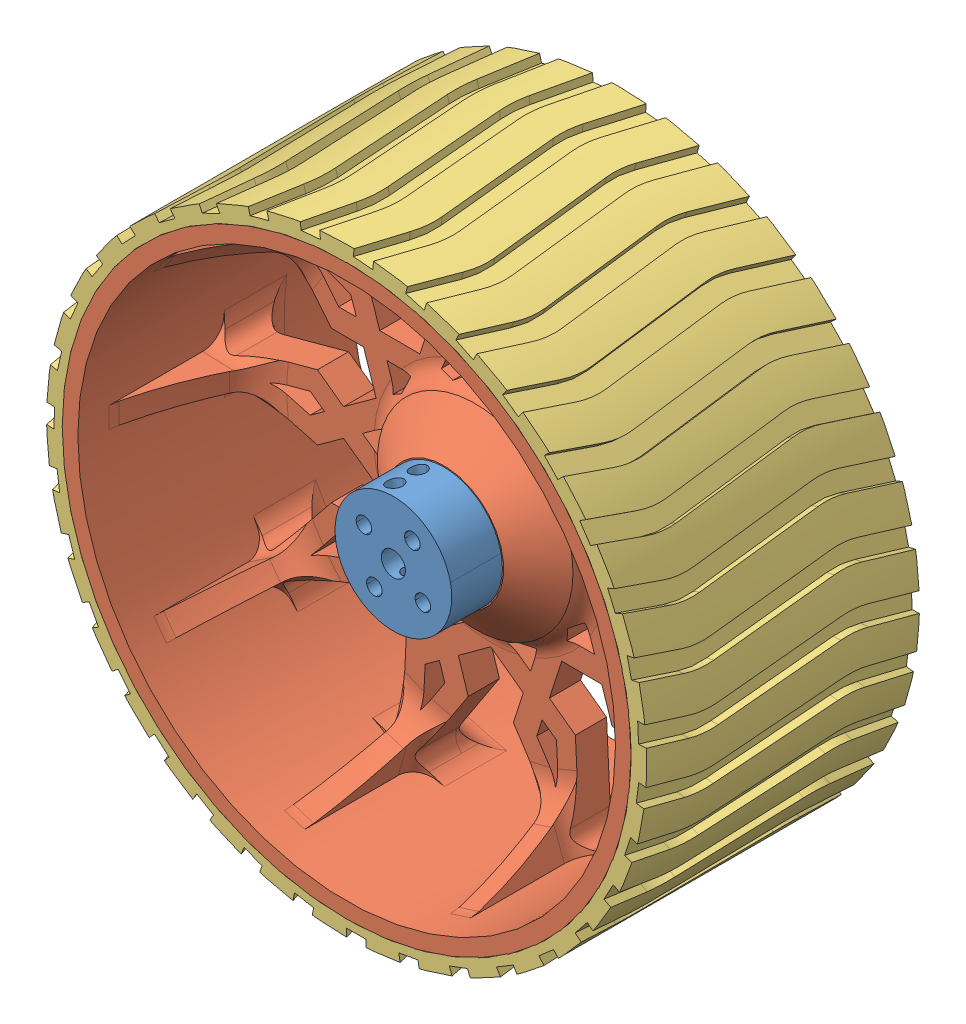
SolidWorks assembly Wheel_assy, configuration Default. Lengths in mm.
Overall size (154 154 80.02).
3 component instances, 3 part files, 6 mates.
Components (placement in the parent):
- Wheel_hub-1: Wheel_hub [Default] at (0 0 10) x (0.977506 0.210909 0) z (0 0 1) size (29.95 29.95 13)
- Wheel_hub_rim-2: Wheel_hub_rim [Default] at origin size (146 146 80.02)
- Wheel_cover-2: Wheel_cover [Default] at (0 0 -35) size (154 154 70)
Mates (geometry in assembly coordinates):
- Coincident4: coincident aligned: plane of Wheel_hub_rim-2 through (0 0 -35) normal (0 0 -1); plane of Wheel_cover-2 through (0 0 -35) normal (0 0 -1)
- Coincident10: coincident aligned: plane of Wheel_hub_rim-2 through (0 0 0) normal (0 0 1)
- Coincident11: coincident aligned: plane of Wheel_hub_rim-2 through (0 0 0) normal (0 1 0)
- Coincident12: coincident aligned: plane of Wheel_hub_rim-2 through (0 0 0) normal (1 0 0)
- Concentric4: concentric aligned: cylinder of Wheel_hub-1 through (0 0 23) axis (0 0 -1) radius 14.975; cylinder of Wheel_hub_rim-2 through (0 0 66) axis (0 0 -1) radius 3.25
- Coincident13: coincident anti-aligned: plane of Wheel_hub-1 through (0 0 10) normal (0 0 -1); plane of Wheel_hub_rim-2 through (0 0 10) normal (0 0 1)
